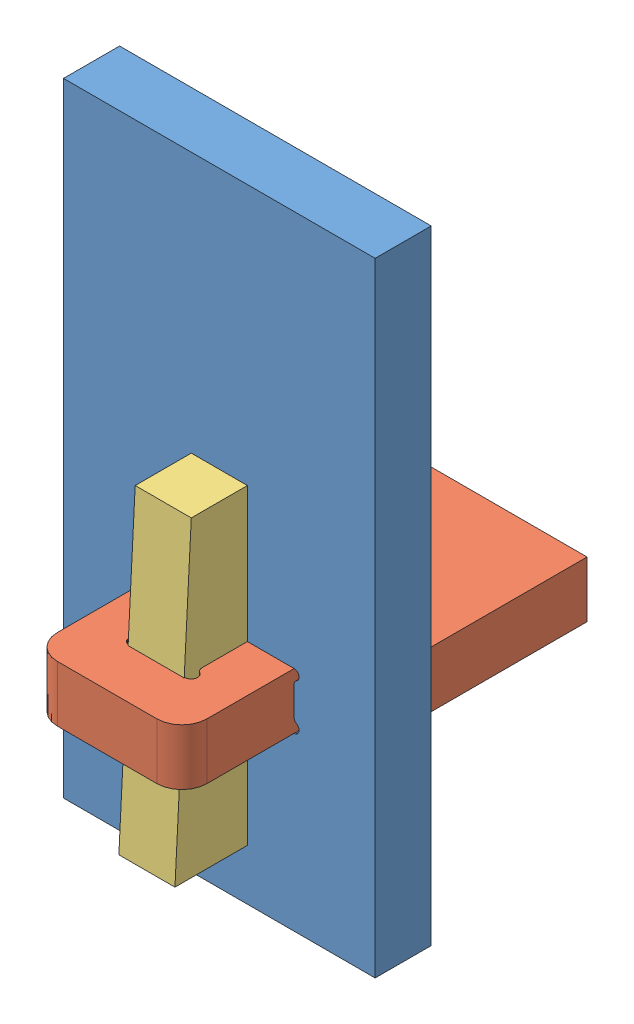
SolidWorks assembly corner-with-wedge, configuration Default. Lengths in mm.
Overall size (25 50 28.5).
3 component instances, 3 part files, 5 mates.
Components (placement in the parent):
- corner-web-1: corner-web [Default] at (-35.5235 -12.2464 1.2346) size (25 50 4.5)
- corner-tabbed-1: corner-tabbed [Default] at (-23.0235 1.5036 1.2346) size (20 4.5 28.5)
- wedge-1: wedge [Default] at (-20.7735 16.8428 5.7346) x (0 -1 0) z (-1 0 0) size (25 5.81 4.5)
Mates (geometry in assembly coordinates):
- Coincident2: coincident anti-aligned: plane of corner-web-1 through (-35.5235 -12.2464 1.2346) normal (0 0 -1); plane of corner-tabbed-1 through (-17.0235 6.0036 1.2346) normal (0 0 1)
- Coincident3: coincident anti-aligned: plane of corner-web-1 through (-17.0235 4.9107 1.2336) normal (-1 0 0); plane of corner-tabbed-1 through (-17.0235 6.0036 12.7346) normal (1 0 0)
- Coincident4: coincident anti-aligned: plane of corner-web-1 through (-29.0235 1.5036 1.2336) normal (0 1 0); plane of corner-tabbed-1 through (-19.0235 1.5036 12.7346) normal (0 -1 0)
- Coincident5: coincident anti-aligned: plane of corner-web-1 through (-35.5235 -12.2464 5.7346) normal (0 0 1); plane of wedge-1 through (-25.2735 16.8428 5.7346) normal (0 0 -1)
- Coincident6: coincident anti-aligned: plane of corner-tabbed-1 through (-25.2735 6.0036 1.2346) normal (1 0 0); plane of wedge-1 through (-25.2735 16.8428 5.7346) normal (-1 0 0)
